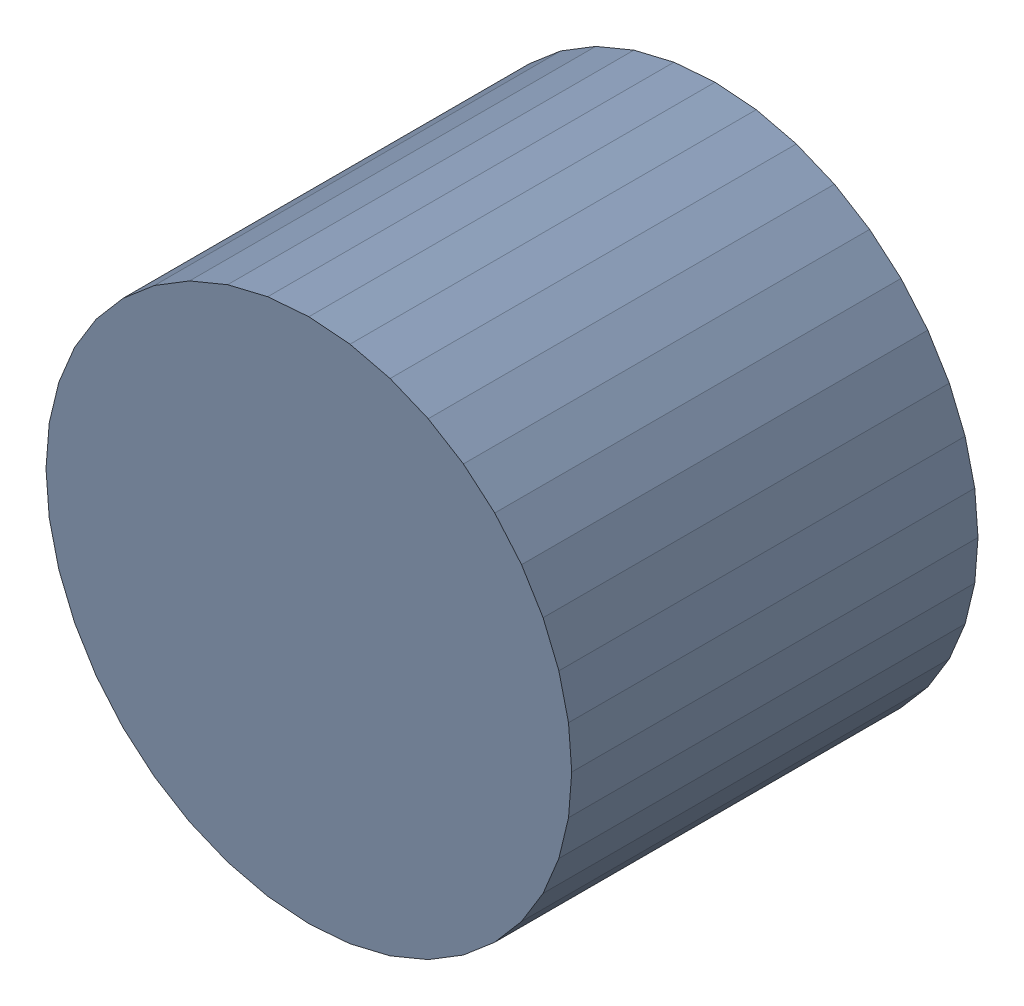
SolidWorks assembly C18Kanaloa_v2.0.0_Power, configuration Default. Lengths in mm.
Overall size (8.02 8.02 6.2).
2 component instances, 1 part files, 0 mates.
Components (placement in the parent):
- 425994496-1: 425994496 [Default] at (80.366 160.68 0) size (8.02 8.02 6.2)
  - Extruded_22-1: Extruded_22 [Default] at origin size (8.02 8.02 6.2)
